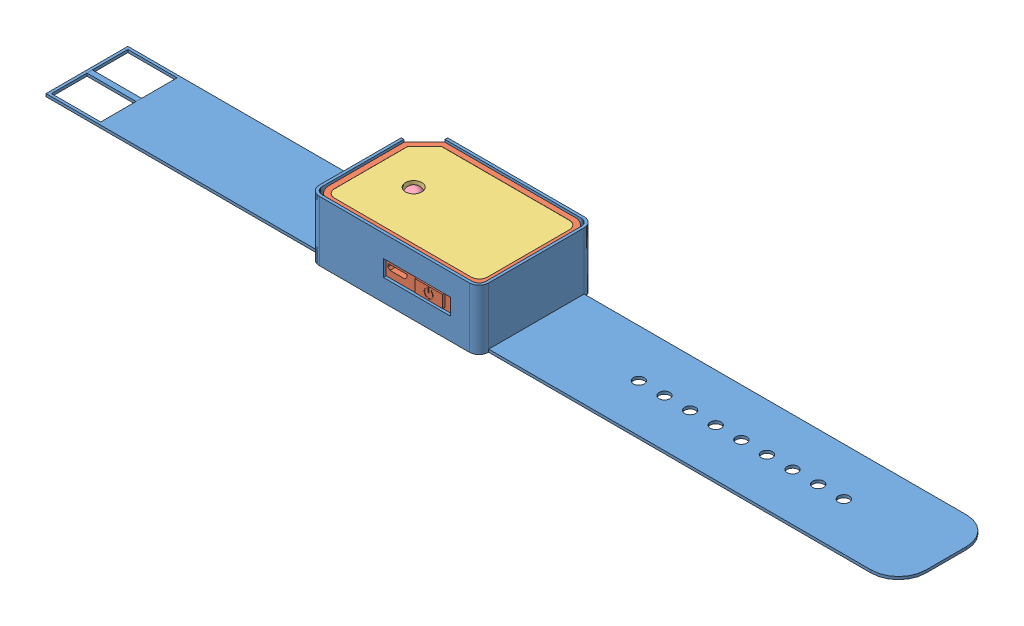
SolidWorks assembly wearable tracker strap, configuration Default. Lengths in mm.
Overall size (312 22 42).
6 component instances, 5 part files, 0 mates.
Components (placement in the parent):
- Part5-1: Part5 [Default] at origin
- strap-1: strap [Default] at (109.8988 146.1957 254.2431) size (312 22 42)
- wearable tracker-2: wearable tracker [Default] at (76.1224 128.467 202.2571) size (60 20.11 41)
  - basenew-1: basenew [Default] at (27.448 18.8337 37.3875) size (60 20 41)
  - topnew-1: topnew [Default] at (46.2829 36.7995 67.6639) size (56 2 36)
  - Lednew-1: Lednew [Default] at (40.831 32.9418 57.477) size (6 6 6)
